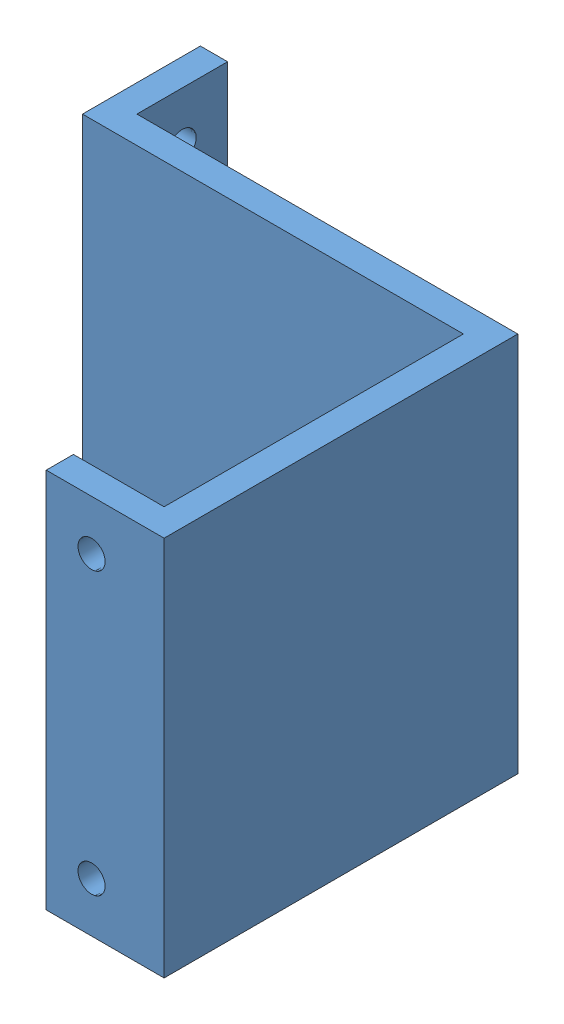
SolidWorks assembly assembly stepper motor f, configuration Default. Lengths in mm.
Overall size (45 42 49).
3 component instances, 3 part files, 4 mates.
Components (placement in the parent):
- sm cover-1: sm cover [Default] at (-18.7835 22.362 59.3551) size (45 42 49)
- stepper motor final-1: stepper motor final [Default] at (-20.2835 22.362 62.3551) (suppressed, hidden)
- sm part2-1: sm part2 [Default] at (-34.2835 22.362 95.3551) x (0 1 0) z (0 0 1) (suppressed, hidden)
Mates (geometry in assembly coordinates):
- Coincident6: coincident: line of assembly; line of assembly; line of sm cover-1 through (0.7165 1.362 95.3551) axis (0 0 -1); line of stepper motor final-1 through (0.7165 1.362 95.3551) axis (0 0 -1)
- Coincident7: coincident: line of assembly; line of assembly; line of stepper motor final-1 through (-41.2835 1.362 95.3551) axis (1 0 0); line of sm part2-1 through (-41.2835 1.362 95.3551) axis (1 0 0)
- Coincident8: coincident: line of assembly; line of assembly; line of stepper motor final-1 through (-41.2835 43.362 95.3551) axis (0 -1 0); line of sm part2-1 through (-41.2835 43.362 95.3551) axis (0 -1 0)
- Coincident9: coincident: line of assembly; line of assembly; line of sm cover-1 through (-41.2835 43.362 62.3551) axis (0 -1 0); line of stepper motor final-1 through (-41.2835 43.362 62.3551) axis (0 -1 0)
